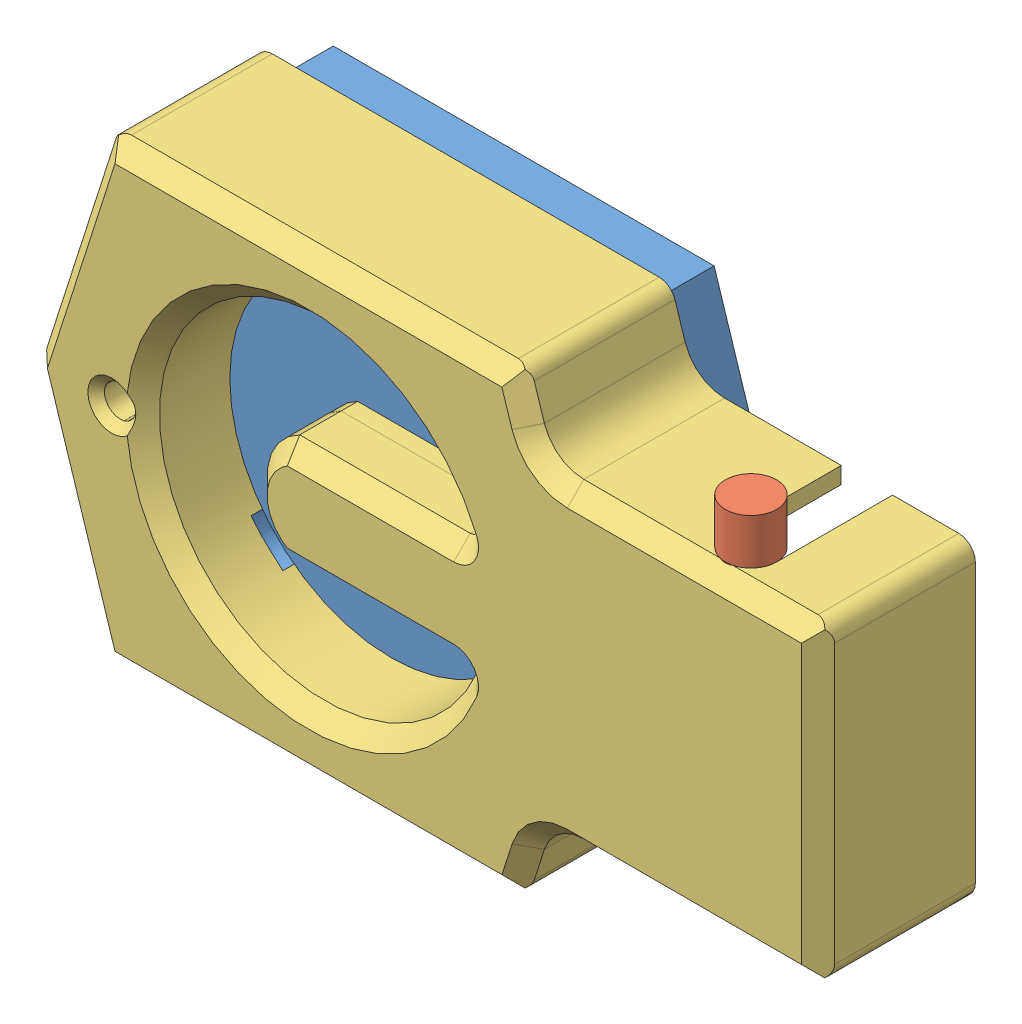
SolidWorks assembly sensor_asm, configuration Default. Lengths in mm.
Overall size (66.05 32.6 4.6).
3 component instances, 3 part files, 2 mates.
Components (placement in the parent):
- indicador-1: indicador [Default] at origin size (62 50 16) (hidden)
- pcb-1: pcb [Default] at (29.75 0 19) size (60 37.5 14.8) (hidden)
- case_test_r1-1: case_test_r1 [Default] at origin size (95.07 55 19.36)
Mates (geometry in assembly coordinates):
- Concentric1: concentric: cylinder of indicador-1 through (23.75 0 16) axis (0 0 -1) radius 3.5; cylinder of pcb-1 through (23.75 0 20.6) axis (0 0 -1) radius 1.75
- Distance1: distance = 3 mm: plane of pcb-1 through (29.75 0 19) normal (0 0 -1); plane of indicador-1 through (0 0 16) normal (0 0 1)
